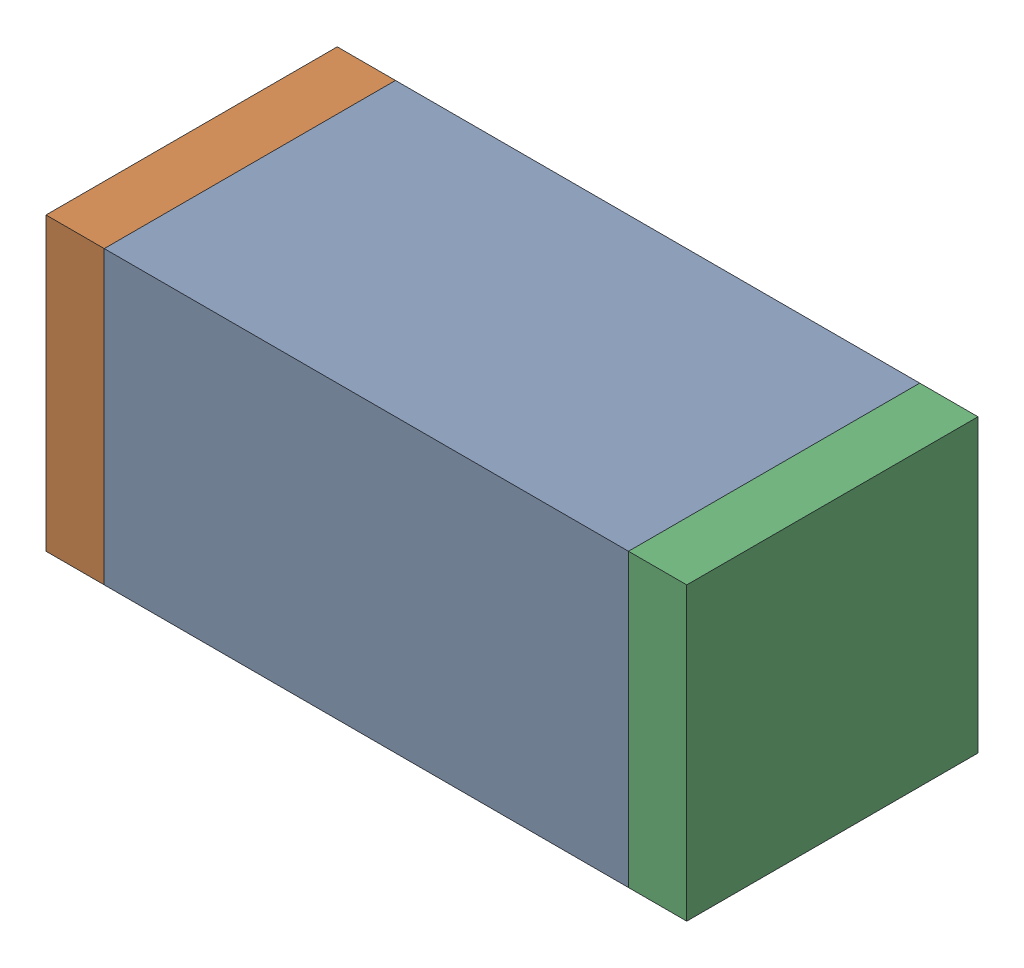
SolidWorks assembly C112, configuration Default. Lengths in mm.
Overall size (1.1 0.5 0.5).
6 component instances, 2 part files, 0 mates.
Components (placement in the parent):
- 836749680-1: 836749680 [Default] at (109 80.45 0) size (0.9 0.5 0.5)
  - Extruded_4-1: Extruded_4 [Default] at origin size (0.9 0.5 0.5)
- 810156080-1: 810156080 [Default] at (108.5 80.45 0) size (0.1 0.5 0.5)
  - Extruded_5-1: Extruded_5 [Default] at origin size (0.1 0.5 0.5)
- 810156080-2: 810156080 [Default] at (109.5 80.45 0) size (0.1 0.5 0.5)
  - Extruded_5-1: Extruded_5 [Default] at origin size (0.1 0.5 0.5)
